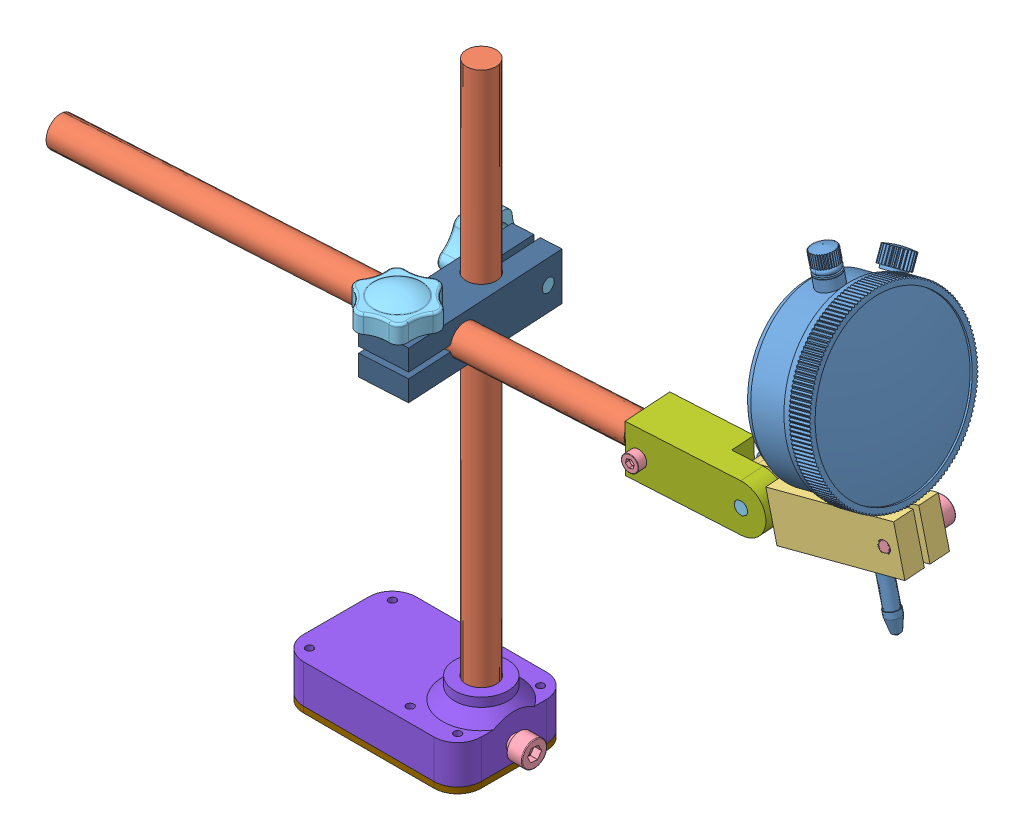
SolidWorks assembly MagneticIndicatorStand, configuration Default. Lengths in mm.
Overall size (285.67 218.5 77.32).
21 component instances, 11 part files, 37 mates.
Components (placement in the parent):
- Dial Indicator-1: Dial Indicator [1..10 mm] at (123.6279 173.3234 8.3001) x (-0.05089 0.00969 -0.998657) z (0.216392 -0.976091 -0.020498) size (60.42 25.7 106.32)
- SteelRod-2: SteelRod [D = 10mm, length = 200mm] at (-120.3983 129.9424 21.8755) x (0.056811 -0.008371 0.99835) z (0.000476 0.999965 0.008357) size (10 200 10)
- SteelRod-3: SteelRod [D = 10mm, length = 200mm] at (0 200.5087 0) x (1 0 0) z (0 0 -1) size (10 200 10)
- IndicatorHolder-1: IndicatorHolder [Custom Part] at (96.5053 128.2048 9.5181) x (-0.056811 0.008371 -0.99835) z (0.974652 0.2172 -0.053641) size (16 16 60)
- socket head cap screw_iso-1: socket head cap screw_iso [ISO 4762 M5 x 16 - 16N] at (149.3727 140.2596 -6.4107) x (0.056811 -0.008371 0.99835) z (-0.74666 0.663468 0.048051) size (21 8.5 8.5)
- socket head cap screw_iso-2: socket head cap screw_iso [ISO 4762 M3 x 6 - 6N] at (73.0359 129.842 22.8872) x (-0.056811 0.008371 -0.99835) z (-0.69019 -0.722865 0.033214) size (9 5.5 5.5)
- ClampingScrewKnob-1: ClampingScrewKnob [M5x16] at (103.848 130.0094 1.1022) x (-0.793441 -0.607327 0.040058) z (-0.056811 0.008371 -0.99835) size (21.59 24 27.35)
- ClampingScrewKnob-2: ClampingScrewKnob [M5x16] at (-8.8393 129.9424 -14.5213) x (-0.045305 -0.603378 -0.796167) z (-0.998385 0 0.056813) size (21.59 24 27.35)
- ClampingScrewKnob-3: ClampingScrewKnob [M5x16] at (1.7044 137.9424 29.9515) x (0.690195 0 -0.723623) z (0 1 0) size (21.59 24 27.35)
- socket head cap screw_iso-5: socket head cap screw_iso [ISO 4762 M5 x 10 - 10N] at (18 6 0) x (-1 0 0) z (0 -0.56518 -0.824967) size (15 8.5 8.5)
- socket countersunk head screw_iso-1: socket countersunk head screw_iso [ISO 10642 - M3 x 10 - 10N] at (6 -2.11 -14) x (0 1 0) z (-0.357031 0 0.934092) size (10 5.54 5.54)
- socket countersunk head screw_iso-2: socket countersunk head screw_iso [ISO 10642 - M3 x 10 - 10N] at (-44 -2.11 -14) x (0 1 0) z (0.821483 0 0.570233) size (10 5.54 5.54)
- socket countersunk head screw_iso-5: socket countersunk head screw_iso [ISO 10642 - M3 x 10 - 10N] at (-10 -2.11 -14) x (0 1 0) z (-0.87933 0 -0.476213) size (10 5.54 5.54)
- socket countersunk head screw_iso-6: socket countersunk head screw_iso [ISO 10642 - M3 x 10 - 10N] at (-44 -2.11 14) x (0 1 0) z (-0.75557 0 0.655068) size (10 5.54 5.54)
- socket countersunk head screw_iso-7: socket countersunk head screw_iso [ISO 10642 - M3 x 10 - 10N] at (-10 -2.11 14) x (0 1 0) z (-0.857294 0 0.514827) size (10 5.54 5.54)
- socket countersunk head screw_iso-8: socket countersunk head screw_iso [ISO 10642 - M3 x 10 - 10N] at (6 -2.11 14) x (0 1 0) z (-0.774019 0 0.633163) size (10 5.54 5.54)
- SecondPartOfIndicatorJoint-1: SecondPartOfIndicatorJoint [Custom Part] at (112.2896 129.9424 8.6345) x (0.056811 -0.008371 0.99835) z (-0.998385 0 0.056813) size (16 16 45)
- BasePart-1: BasePart [Casting Aluminum Part] at origin size (60 20 38)
- Lid-1: Lid [Custom Part] at (-19 0 0) x (1 0 0) z (0 0 -1) size (60 2 38)
- MainJoint-1: MainJoint [Custom Part] at (1.9884 129.9424 34.9435) x (-0.998385 0 0.056813) z (-0.056813 0 -0.998385) size (16 16 55)
- Neodymium Magnet Square-1: Neodymium Magnet Square [25x25x8 - 35 kg] at (-27 1 0) size (25 8 25)
Mates (geometry in assembly coordinates):
- Concentric1: concentric anti-aligned: circle of Dial Indicator-1; cylinder of Part4^MagneticIndicatorStand-1 through (142.0958 130.1701 6.9403) axis (-0.216392 0.976091 0.020498) radius 4.05
- Concentric2: concentric aligned: cylinder of Part4^MagneticIndicatorStand-1 through (150.5657 140.0838 14.5557) axis (-0.056811 0.008371 -0.99835) radius 2.05; cylinder of socket head cap screw_iso-1 through (147.5689 140.5254 -38.1083) axis (-0.056811 0.008371 -0.99835) radius 2.5
- Coincident1: coincident anti-aligned: plane of Part4^MagneticIndicatorStand-1 through (156.2611 133.495 -1.8511) normal (-0.056811 0.008371 -0.99835); plane of socket head cap screw_iso-1 through (152.4735 143.3974 -1.5526) normal (0.056811 -0.008371 0.99835)
- Concentric3: concentric aligned: cylinder of SteelRod^MagneticIndicatorStand-1 through (79.2786 129.9424 10.513) axis (-0.998385 0 0.056813) radius 5; cylinder of Part1^MagneticIndicatorStand-1 through (67.3623 129.9424 11.191) axis (-0.998385 0 0.056813) radius 5.1
- Coincident2: coincident anti-aligned: plane of SteelRod^MagneticIndicatorStand-1 through (79.2786 129.9424 10.513) normal (0.998385 0 -0.056813); circle of Part1^MagneticIndicatorStand-1
- Concentric4: concentric anti-aligned: cylinder of Part4^MagneticIndicatorStand-1 through (104.757 129.8755 17.0758) axis (-0.056811 0.008371 -0.99835) radius 2.55; cylinder of Part1^MagneticIndicatorStand-1 through (104.757 129.8755 17.0758) axis (0.056811 -0.008371 0.99835) radius 2.1
- Coincident3: coincident anti-aligned: plane of Part4^MagneticIndicatorStand-1 through (96.5053 128.2048 9.5181) normal (0.056811 -0.008371 0.99835); plane of Part1^MagneticIndicatorStand-1 through (112.2896 129.9424 8.6345) normal (-0.056811 0.008371 -0.99835)
- Coincident4: coincident anti-aligned: plane of Part4^MagneticIndicatorStand-1 through (156.2611 133.495 -1.8511) normal (-0.056811 0.008371 -0.99835); plane of ClampingScrewKnob-1 through (103.848 130.0094 1.1022) normal (0.056811 -0.008371 0.99835)
- Concentric5: concentric aligned: cylinder of Part4^MagneticIndicatorStand-1 through (104.757 129.8755 17.0758) axis (-0.056811 0.008371 -0.99835) radius 2.55; cylinder of ClampingScrewKnob-1 through (104.757 129.8755 17.0758) axis (-0.056811 0.008371 -0.99835) radius 2.5
- Distance1: distance = 1 mm: point of Dial Indicator-1; plane of Part4^MagneticIndicatorStand-1 through (152.7988 149.1125 -1.5232) normal (-0.216392 0.976091 0.020498)
- Concentric6: concentric aligned: cylinder of Part1^MagneticIndicatorStand-1 through (72.8087 129.8755 18.8938) axis (0.056811 -0.008371 0.99835) radius 1.25; cylinder of socket head cap screw_iso-2 through (74.8397 129.5762 54.5848) axis (0.056811 -0.008371 0.99835) radius 1.5
- Coincident7: coincident anti-aligned: plane of SteelRod^MagneticIndicatorStand-1 through (80.5798 124.9175 13.4017) normal (0.056811 -0.008371 0.99835); plane of socket head cap screw_iso-2 through (73.4044 129.0747 13.8449) normal (-0.056811 0.008371 -0.99835)
- Concentric7: concentric aligned: cylinder of SteelRod^MagneticIndicatorStand-2 through (0 0.5087 0) axis (0 1 0) radius 5; cylinder of Base-1 through (0 20 0) axis (0 1 0) radius 5.1
- Concentric15: concentric aligned: cylinder of Base-1 through (11 6 0) axis (1 0 0) radius 2.1; cylinder of socket head cap screw_iso-5 through (49.75 6 0) axis (1 0 0) radius 2.5
- Coincident19: coincident anti-aligned: plane of SteelRod^MagneticIndicatorStand-2 through (3 -0.6262 5) normal (1 0 0); plane of socket head cap screw_iso-5 through (3 7.6953 -1.1614) normal (-1 0 0)
- Concentric23: concentric aligned: cylinder of Base-1 through (6 0 -14) axis (0 -1 0) radius 1.25; cylinder of socket countersunk head screw_iso-1 through (6 -2.11 -14) axis (0 -1 0) radius 1.5
- Concentric25: concentric aligned: cylinder of Base-1 through (-44 0 -14) axis (0 -1 0) radius 1.25; cylinder of socket countersunk head screw_iso-2 through (-44 -2.11 -14) axis (0 -1 0) radius 1.5
- Coincident31: coincident anti-aligned: plane of Base-1 through (0 0 0) normal (0 -1 0); plane of Lid-1 through (3 0 11) normal (0 1 0)
- Concentric26: concentric aligned: cylinder of Base-1 through (6 0 -14) axis (0 -1 0) radius 1.25; cylinder of Lid-1 through (6 -2 -14) axis (0 -1 0) radius 1.55
- Concentric28: concentric aligned: cylinder of socket countersunk head screw_iso-8 through (6 -2.11 14) axis (0 -1 0) radius 1.5; cylinder of Lid-1 through (6 -2 14) axis (0 -1 0) radius 1.55
- Coincident33: coincident aligned: cone of socket countersunk head screw_iso-8 through (6 -1.52 14) axis (0 1 0); cone of Lid-1 through (6 -2 14) axis (0 1 0)
- Concentric30: concentric aligned: cylinder of socket countersunk head screw_iso-1 through (6 -2.11 -14) axis (0 -1 0) radius 1.5; cylinder of Lid-1 through (6 -2 -14) axis (0 -1 0) radius 1.55
- Coincident34: coincident aligned: cone of socket countersunk head screw_iso-1 through (6 -1.52 -14) axis (0 1 0); cone of Lid-1 through (6 -2 -14) axis (0 1 0)
- Concentric31: concentric aligned: cylinder of socket countersunk head screw_iso-7 through (-10 -2.11 14) axis (0 -1 0) radius 1.5; cylinder of Lid-1 through (-10 -2 14) axis (0 -1 0) radius 1.55
- Coincident35: coincident aligned: cone of socket countersunk head screw_iso-7 through (-10 -1.52 14) axis (0 1 0); cone of Lid-1 through (-10 -2 14) axis (0 1 0)
- Concentric32: concentric aligned: cylinder of socket countersunk head screw_iso-6 through (-44 -2.11 14) axis (0 -1 0) radius 1.5; cylinder of Lid-1 through (-44 -2 14) axis (0 -1 0) radius 1.55
- Coincident36: coincident aligned: cone of socket countersunk head screw_iso-6 through (-44 -1.52 14) axis (0 1 0); cone of Lid-1 through (-44 -2 14) axis (0 1 0)
- Concentric33: concentric aligned: cylinder of socket countersunk head screw_iso-5 through (-10 -2.11 -14) axis (0 -1 0) radius 1.5; cylinder of Lid-1 through (-10 -2 -14) axis (0 -1 0) radius 1.55
- Coincident37: coincident aligned: cone of socket countersunk head screw_iso-5 through (-10 -1.52 -14) axis (0 1 0); cone of Lid-1 through (-10 -2 -14) axis (0 1 0)
- Concentric35: concentric aligned: cylinder of SteelRod^MagneticIndicatorStand-2 through (0 0.5087 0) axis (0 1 0) radius 5; cylinder of Part6-1 through (0 137.9424 0) axis (0 1 0) radius 5.1
- Concentric36: concentric aligned: cylinder of ClampingScrewKnob-2 through (7.1349 129.9424 -15.4303) axis (-0.998385 0 0.056813) radius 2.5; cylinder of Part6-1 through (-8.8393 129.9424 -14.5213) axis (-0.998385 0 0.056813) radius 2.55
- Coincident39: coincident anti-aligned: plane of ClampingScrewKnob-2 through (-8.8393 129.9424 -14.5213) normal (0.998385 0 -0.056813); plane of Part6-1 through (-9.1233 121.9424 -19.5132) normal (-0.998385 0 0.056813)
- Concentric37: concentric anti-aligned: cylinder of SteelRod^MagneticIndicatorStand-1 through (79.2786 129.9424 10.513) axis (-0.998385 0 0.056813) radius 5; cylinder of Part6-1 through (8.8393 129.9424 14.5213) axis (0.998385 0 -0.056813) radius 5.1
- Concentric38: concentric aligned: cylinder of ClampingScrewKnob-3 through (1.7044 121.9424 29.9515) axis (0 1 0) radius 2.5; cylinder of Part6-1 through (1.7044 137.9424 29.9515) axis (0 1 0) radius 2.55
- Coincident40: coincident anti-aligned: plane of ClampingScrewKnob-3 through (1.7044 137.9424 29.9515) normal (0 -1 0); plane of Part6-1 through (-9.1233 137.9424 -19.5132) normal (0 1 0)
- ProfileCenter2: profile center anti-aligned: plane of Base-1 through (0 9 0) normal (0 -1 0); plane of Neodymium Magnet Square-1 through (-27 9 0) normal (0 1 0)
- Concentric40: concentric aligned: cylinder of socket countersunk head screw_iso-5 through (-10 -2.11 -14) axis (0 -1 0) radius 1.5; cylinder of Base-1 through (-10 0 -14) axis (0 -1 0) radius 1.25
